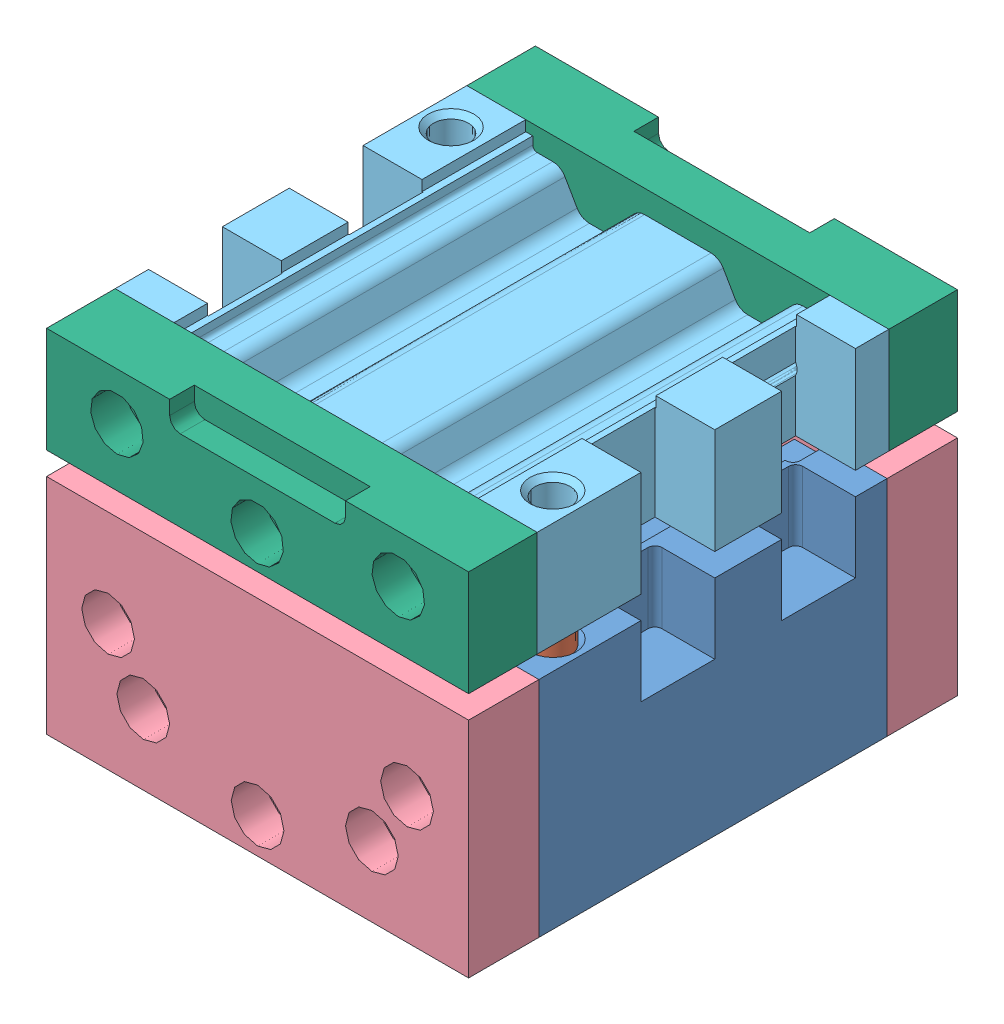
SolidWorks assembly Сборка, configuration По умолчанию. Lengths in mm.
Overall size (120 100 139).
10 component instances, 6 part files, 26 mates.
Components (placement in the parent):
- Матрица пресс-формы трак-1: Матрица пресс-формы трак [По умолчанию] at (94.4955 113.7729 76.599) x (-1 0 0) z (0 -1 0) size (120 99 63.5)
- Направляющая-1: Направляющая [По умолчанию] at (134.3195 83.7729 119.5159) x (0 1 0) z (-0.942376 0 0.334555) size (55 10 10)
- Направляющая-2: Направляющая [По умолчанию] at (30.3195 83.7729 44.5159) x (0 1 0) z (-0.954844 0 0.297108) size (55 10 10)
- Подстановка-1: Подстановка [По умолчанию] at (85.2823 100.5229 55.4864) x (0 1 0) z (-0.987622 0 -0.156852) size (36.5 12 12)
- Подстановка-2: Подстановка [По умолчанию] at (83.6486 100.5229 111.7054) x (0 1 0) z (-0.443057 0 -0.896493) size (36.5 12 12)
- Боковина пресс-формы-1: Боковина пресс-формы [По умолчанию] at (82.3195 82.0229 131.5159) x (1 0 0) z (0 -1 0) size (120 20 63.5)
- Боковина пресс-формы-2: Боковина пресс-формы [По умолчанию] at (82.3195 82.0229 32.5159) x (-1 0 0) z (0 -1 0) size (120 20 63.5)
- Пуансон (на бис, дымись канабис)-2: Пуансон (на бис, дымись канабис) [По умолчанию] at (69.8379 150.2729 72.2482) x (-1 0 0) z (0 0 1) size (120 30 100)
- Боковина пуансона-5: Боковина пуансона [По умолчанию] at (82.3195 135.2729 132.0159) x (1 0 0) z (0 -1 0) size (120 19.5 30)
- Боковина пуансона-6: Боковина пуансона [По умолчанию] at (82.3195 135.2729 32.0159) x (-1 0 0) z (0 -1 0) size (120 19.5 30)
Mates (geometry in assembly coordinates):
- Совпадение1: coincident anti-aligned: plane of Матрица пресс-формы трак-1 through (134.3195 83.7729 119.5159) normal (0 1 0); plane of Направляющая-1 through (134.3195 83.7729 119.5159) normal (0 -1 0)
- Концентричный2: concentric anti-aligned: cylinder of Матрица пресс-формы трак-1 through (134.3195 83.7729 119.5159) axis (0 1 0) radius 5; cylinder of Направляющая-1 through (134.3195 83.7729 119.5159) axis (0 -1 0) radius 5
- Совпадение2: coincident anti-aligned: plane of Матрица пресс-формы трак-1 through (30.3195 83.7729 44.5159) normal (0 1 0); plane of Направляющая-2 through (30.3195 83.7729 44.5159) normal (0 -1 0)
- Концентричный3: concentric anti-aligned: cylinder of Матрица пресс-формы трак-1 through (30.3195 83.7729 44.5159) axis (0 1 0) radius 5; cylinder of Направляющая-2 through (30.3195 83.7729 44.5159) axis (0 -1 0) radius 5
- Совпадение3: coincident anti-aligned: plane of Матрица пресс-формы трак-1 through (82.3195 83.7729 55.0159) normal (0 1 0); plane of Подстановка-1 through (82.3195 83.7729 55.0159) normal (0 -1 0)
- Концентричный4: concentric anti-aligned: cylinder of Матрица пресс-формы трак-1 through (82.3195 83.7729 55.0159) axis (0 1 0) radius 6; cylinder of Подстановка-1 through (82.3195 83.7729 55.0159) axis (0 -1 0) radius 6
- Совпадение4: coincident anti-aligned: plane of Матрица пресс-формы трак-1 through (82.3195 83.7729 109.0159) normal (0 1 0); plane of Подстановка-2 through (82.3195 83.7729 109.0159) normal (0 -1 0)
- Концентричный5: concentric anti-aligned: cylinder of Матрица пресс-формы трак-1 through (82.3195 83.7729 109.0159) axis (0 1 0) radius 6; cylinder of Подстановка-2 through (82.3195 83.7729 109.0159) axis (0 -1 0) radius 6
- Совпадение7: coincident anti-aligned: plane of Матрица пресс-формы трак-1 through (142.3195 50.2729 131.5159) normal (0 0 1); plane of Боковина пресс-формы-1 through (82.3195 82.0229 131.5159) normal (0 0 -1)
- Концентричный8: concentric aligned: cylinder of Матрица пресс-формы трак-1 through (82.3195 60.2729 101.5159) axis (0 0 1) radius 3.4; cylinder of Боковина пресс-формы-1 through (82.3195 60.2729 151.5159) axis (0 0 1) radius 4.25
- Концентричный9: concentric aligned: cylinder of Матрица пресс-формы трак-1 through (82.3195 60.2729 62.5159) axis (0 0 -1) radius 3.4; cylinder of Боковина пресс-формы-2 through (82.3195 60.2729 12.5159) axis (0 0 -1) radius 4.25
- Совпадение8: coincident anti-aligned: plane of Матрица пресс-формы трак-1 through (142.3195 50.2729 32.5159) normal (0 0 -1); plane of Боковина пресс-формы-2 through (82.3195 82.0229 32.5159) normal (0 0 1)
- Концентричный11: concentric aligned: cylinder of Направляющая-2 through (30.3195 83.7729 44.5159) axis (0 -1 0) radius 5; cylinder of Пуансон (на бис, дымись канабис)-2 through (30.3195 220.2729 44.5159) axis (0 -1 0) radius 5
- Совпадение9: coincident anti-aligned: circle of Подстановка-1; plane of Пуансон (на бис, дымись канабис)-2 through (69.8379 120.2729 72.2482) normal (0 -1 0)
- Концентричный14: concentric aligned: cylinder of Пуансон (на бис, дымись канабис)-2 through (122.3195 136.7729 105.2659) axis (0 0 1) radius 3.4; cylinder of Боковина пуансона-5 through (122.3195 136.7729 151.5159) axis (0 0 1) radius 4.5
- Совпадение11: coincident anti-aligned: plane of Пуансон (на бис, дымись канабис)-2 through (142.3195 120.2729 132.0159) normal (0 0 1); plane of Боковина пуансона-5 through (82.3195 135.2729 132.0159) normal (0 0 -1)
- Концентричный15: concentric aligned: cylinder of Пуансон (на бис, дымись канабис)-2 through (122.3195 136.7729 58.7659) axis (0 0 -1) radius 3.4; cylinder of Боковина пуансона-6 through (122.3195 136.7729 12.5159) axis (0 0 -1) radius 4.5
- Совпадение12: coincident anti-aligned: plane of Пуансон (на бис, дымись канабис)-2 through (142.3195 120.2729 32.0159) normal (0 0 -1); plane of Боковина пуансона-6 through (82.3195 135.2729 32.0159) normal (0 0 1)
- Параллельность1: parallel aligned: cylinder of Направляющая-1 through (134.3195 83.7729 119.5159) axis (0 -1 0) radius 5; cylinder of Пуансон (на бис, дымись канабис)-2 through (134.2575 220.2729 119.5159) axis (0 -1 0) radius 5
- Концентричный17: concentric aligned: cylinder of Направляющая-2 through (30.3195 83.7729 44.5159) axis (0 -1 0) radius 5; cylinder of Пуансон (на бис, дымись канабис)-2 through (30.3195 220.2729 44.5159) axis (0 -1 0) radius 5
- Совпадение13: coincident aligned: plane of Пуансон (на бис, дымись канабис)-2 through (22.3195 120.2729 32.0159) normal (-1 0 0); plane of Боковина пуансона-5 through (22.3195 120.2729 151.5159) normal (-1 0 0)
- Совпадение14: coincident aligned: plane of Пуансон (на бис, дымись канабис)-2 through (22.3195 120.2729 32.0159) normal (-1 0 0); plane of Боковина пуансона-6 through (22.3195 120.2729 12.5159) normal (-1 0 0)
- Параллельность2: parallel aligned: cylinder of Боковина пресс-формы-1 through (124.8195 86.2729 151.5159) axis (0 0 1) radius 4.25; cylinder of Матрица пресс-формы трак-1 through (124.8195 86.2729 101.5159) axis (0 0 1) radius 3.4
- Совпадение16: coincident aligned: plane of Матрица пресс-формы трак-1 through (142.3195 50.2729 32.5159) normal (1 0 0); plane of Боковина пресс-формы-1 through (142.3195 50.2729 151.5159) normal (1 0 0)
- Совпадение17: coincident aligned: plane of Матрица пресс-формы трак-1 through (142.3195 50.2729 32.5159) normal (1 0 0); plane of Боковина пресс-формы-2 through (142.3195 50.2729 12.5159) normal (1 0 0)
- Совпадение18: coincident aligned: plane of Матрица пресс-формы трак-1 through (142.3195 50.2729 32.5159) normal (1 0 0); plane of Пуансон (на бис, дымись канабис)-2 through (142.3195 120.2729 32.0159) normal (1 0 0)
